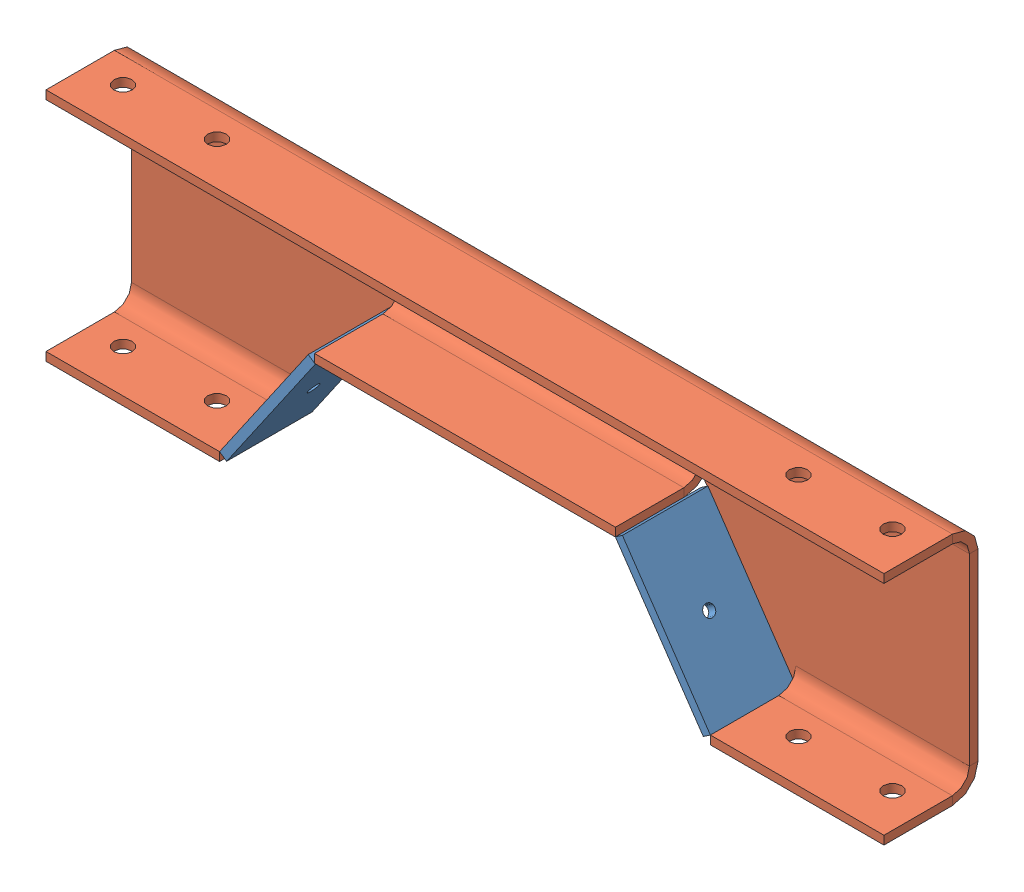
SolidWorks assembly 2575-CC2, configuration Default. Lengths in mm.
Overall size (622.3 174.62 69.85).
3 component instances, 2 part files, 9 mates.
Components (placement in the parent):
- 2575-CC2 DTL2-1: 2575-CC2 DTL2 [Default] at (-182.245 -168.275 69.85) x (0.568105 0.822956 0) z (-0.822956 0.568105 0) size (115.92 63.5 6.35)
- 2575-CC2 DTL2-2: 2575-CC2 DTL2 [Default] at (176.999 -171.853 69.85) x (-0.563461 0.826143 0) z (-0.826143 -0.563461 0) size (115.92 63.5 6.35)
- 2575-CC2 DTL1-1: 2575-CC2 DTL1 [FLAT] at origin size (622.3 174.62 69.85)
Mates (geometry in assembly coordinates):
- Coincident49: coincident aligned: line of ?
- Coincident54: coincident anti-aligned: unknown of 2575-CC2 DTL2-1
- Coincident56: coincident anti-aligned: plane of ? through (155.7829 -55.4178 6.35) normal (0 0 -1)
- Coincident67: coincident anti-aligned: unknown of 2575-CC2 DTL2-1
- Coincident70: coincident: line of ?; plane of ?
- Coincident71: coincident anti-aligned: unknown of 2575-CC2 DTL2-1
- Coincident72: coincident aligned: plane of ?; plane of assembly
- Coincident73: coincident aligned: plane of ?; plane of assembly
- Coincident74: coincident aligned: plane of ?; plane of assembly
